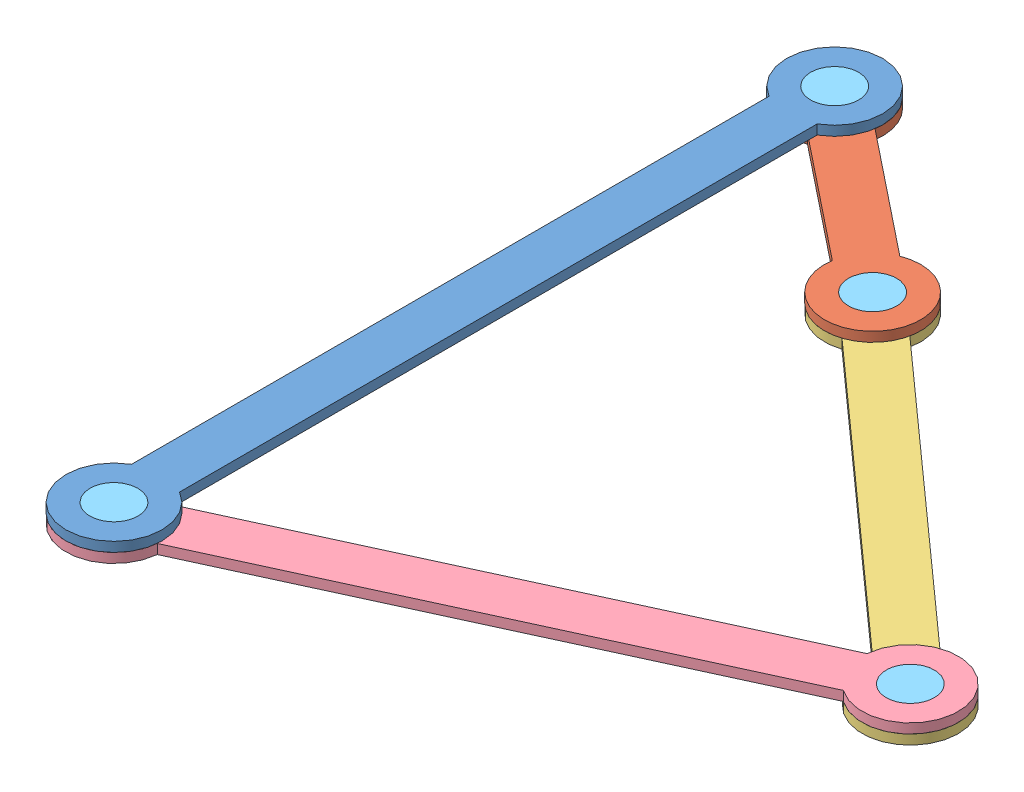
SolidWorks assembly 組合件1, configuration 預設. Lengths in mm.
Overall size (141.78 6 177.31).
8 component instances, 5 part files, 15 mates.
Components (placement in the parent):
- 零件4-2: 零件4 [預設] at (-39.8264 -73.7523 52.2452) x (0 0 -1) z (1 0 0) size (170 2 20)
- 零件1-2: 零件1 [預設] at (-39.8264 -75.7523 -97.7548) x (0.781712 0 0.62364) z (-0.62364 0 0.781712) size (70 2 20)
- 零件2-2: 零件2 [預設] at (-0.7408 -77.7523 -66.5728) x (0.745224 0 0.666814) z (-0.666814 0 0.745224) size (120 2 20)
- 零件3-3: 零件3 [預設] at (-39.8264 -75.7523 52.2452) x (0.908864 0 -0.417093) z (0.417093 0 0.908864) size (145 2 20)
- 零件5-5: 零件5 [預設] at (-0.7408 -77.7523 -66.5728) size (10 4 10)
- 零件5-6: 零件5 [預設] at (-39.8264 -75.7523 52.2452) size (10 4 10)
- 零件5-7: 零件5 [預設] at (-39.8264 -75.7523 -97.7548) size (10 4 10)
- 零件5-8: 零件5 [預設] at (73.7815 -77.7523 0.1086) size (10 4 10)
Mates (geometry in assembly coordinates):
- 重合/共線/共點1: coincident anti-aligned: plane of 零件4-2 through (-39.8264 -73.7523 -97.7548) normal (0 -1 0); plane of 零件1-2 through (-0.7408 -73.7523 -66.5728) normal (0 1 0)
- 同軸心1: concentric aligned: cylinder of 零件4-2 through (-39.8264 -71.7523 -97.7548) axis (0 -1 0) radius 5; cylinder of 零件1-2 through (-39.8264 -73.7523 -97.7548) axis (0 -1 0) radius 5
- 重合/共線/共點2: coincident anti-aligned: plane of 零件1-2 through (-0.7408 -75.7523 -66.5728) normal (0 -1 0); plane of 零件2-2 through (73.7815 -75.7523 0.1086) normal (0 1 0)
- 同軸心2: concentric aligned: cylinder of 零件1-2 through (-0.7408 -73.7523 -66.5728) axis (0 -1 0) radius 5; cylinder of 零件2-2 through (-0.7408 -75.7523 -66.5728) axis (0 -1 0) radius 5
- 重合/共線/共點3: coincident anti-aligned: plane of 零件2-2 through (73.7815 -75.7523 0.1086) normal (0 1 0); plane of 零件3-3 through (73.7815 -75.7523 0.1086) normal (0 -1 0)
- 同軸心3: concentric aligned: cylinder of 零件2-2 through (73.7815 -75.7523 0.1086) axis (0 -1 0) radius 5; cylinder of 零件3-3 through (73.7815 -73.7523 0.1086) axis (0 -1 0) radius 5
- 同軸心4: concentric aligned: cylinder of 零件4-2 through (-39.8264 -71.7523 52.2452) axis (0 -1 0) radius 5; cylinder of 零件3-3 through (-39.8264 -73.7523 52.2452) axis (0 -1 0) radius 5
- 重合/共線/共點4: coincident aligned: plane of 零件4-2 through (-39.8264 -71.7523 -97.7548) normal (0 1 0); plane of 零件5-7 through (-39.8264 -71.7523 -97.7548) normal (0 1 0)
- 同軸心5: concentric aligned: cylinder of 零件4-2 through (-39.8264 -71.7523 -97.7548) axis (0 -1 0) radius 5; cylinder of 零件5-7 through (-39.8264 -71.7523 -97.7548) axis (0 -1 0) radius 5
- 重合/共線/共點5: coincident aligned: plane of 零件3-3 through (73.7815 -73.7523 0.1086) normal (0 1 0); plane of 零件5-8 through (73.7815 -73.7523 0.1086) normal (0 1 0)
- 同軸心6: concentric aligned: cylinder of 零件3-3 through (73.7815 -73.7523 0.1086) axis (0 -1 0) radius 5; cylinder of 零件5-8 through (73.7815 -73.7523 0.1086) axis (0 -1 0) radius 5
- 重合/共線/共點6: coincident aligned: plane of 零件1-2 through (-0.7408 -73.7523 -66.5728) normal (0 1 0); plane of 零件5-5 through (-0.7408 -73.7523 -66.5728) normal (0 1 0)
- 同軸心7: concentric aligned: cylinder of 零件1-2 through (-0.7408 -73.7523 -66.5728) axis (0 -1 0) radius 5; cylinder of 零件5-5 through (-0.7408 -73.7523 -66.5728) axis (0 -1 0) radius 5
- 重合/共線/共點7: coincident aligned: plane of 零件4-2 through (-39.8264 -71.7523 -97.7548) normal (0 1 0); circle of 零件5-6
- 同軸心8: concentric aligned: cylinder of 零件4-2 through (-39.8264 -71.7523 52.2452) axis (0 -1 0) radius 5; cylinder of 零件5-6 through (-39.8264 -71.7523 52.2452) axis (0 -1 0) radius 5
